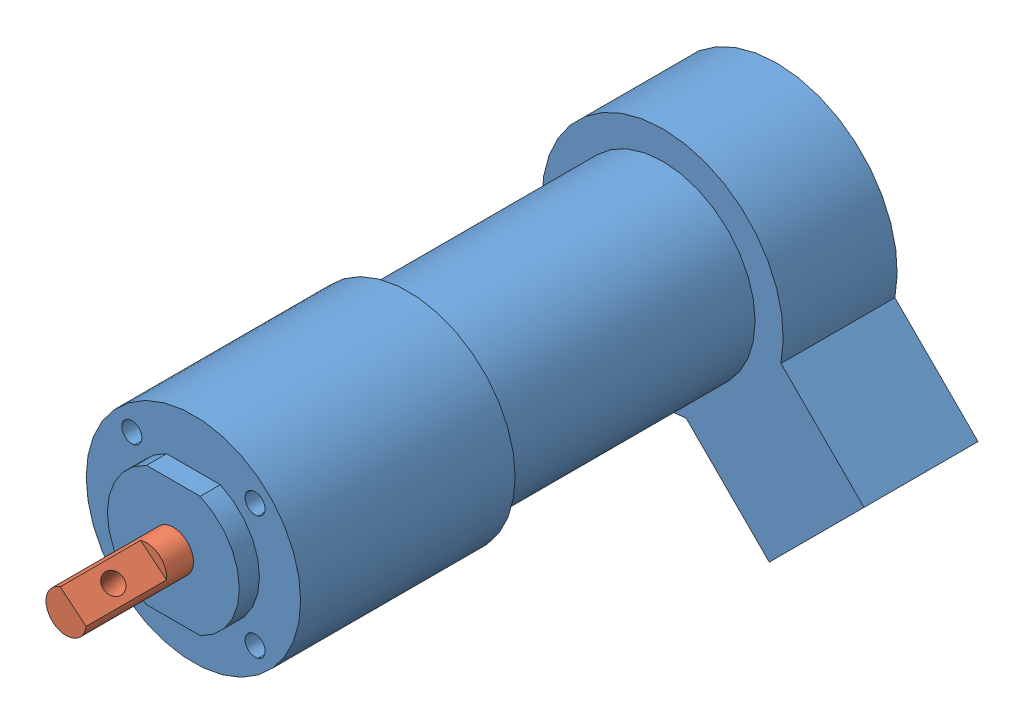
SolidWorks assembly Dc_motorV2, configuration Default. Lengths in mm.
2 component instances, 2 part files, 1 mates.
Components (placement in the parent):
- Motor_bodyV2-2: Motor_bodyV2 [Default] at (34.2418 49.7061 110.5294) size (48.05 48.05 90)
- Motor_shaftV2-2: Motor_shaftV2 [Default] at (34.2418 49.7061 113.5294) x (0.771631 -0.63607 0) z (0 0 1) size (6 6 16)
Mates (geometry in assembly coordinates):
- Coincident3: coincident aligned: circle of Motor_bodyV2-2; circle of Motor_shaftV2-2
